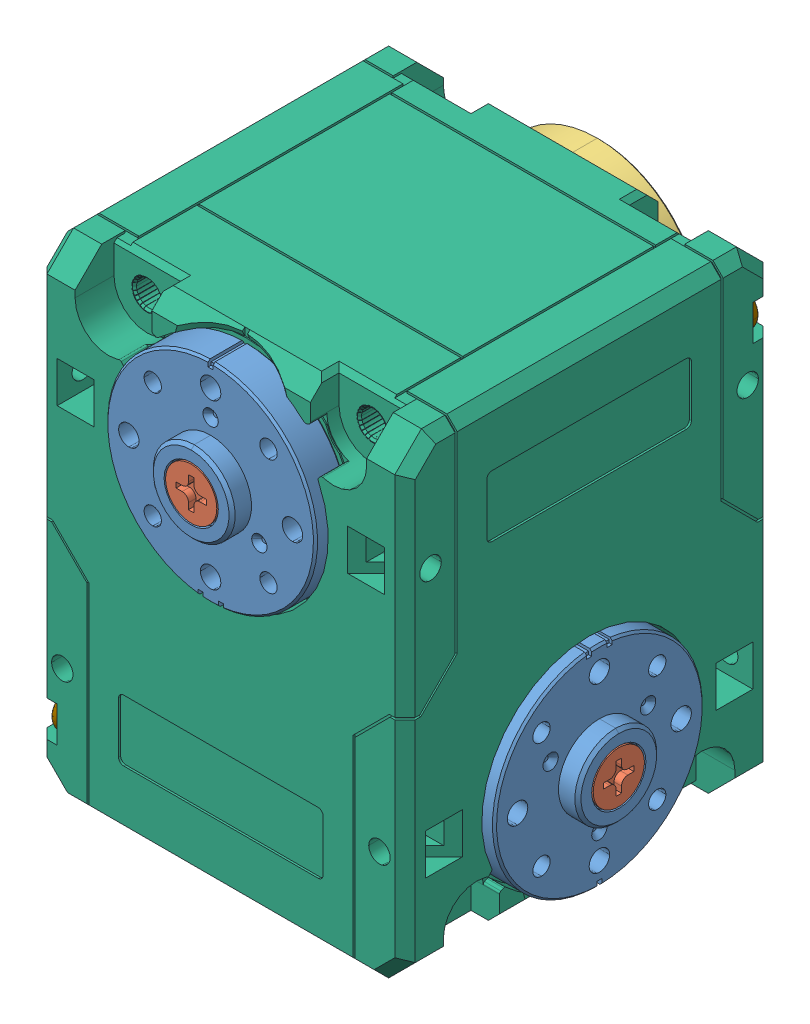
SolidWorks assembly 2XL-430, configuration Default. Lengths in mm.
Overall size (40.9 46.5 40.9).
34 component instances, 11 part files, 0 mates.
Components (placement in the parent):
- 2XL-430.stp-1: 2XL-430.stp [Default] at origin size (40.9 46.5 40.9)
  - DC11_A01_HORN_REF_ASM.stp-1: DC11_A01_HORN_REF_ASM.stp [Default] at (15.5 -12 0) x (0 -1 0) z (0 0 1) size (20.5 6.01 20.5)
    - DC11_A01_HORN_REF.stp-1: DC11_A01_HORN_REF.stp [Default] at origin size (20.5 5.4 20.5)
    - FHS_M2_5X06_NYLOK.stp-1: FHS_M2_5X06_NYLOK.stp [Default] at (0 3.95 0) size (5 6.01 5)
  - DC11_A01_HORN_REF_ASM.stp-2: DC11_A01_HORN_REF_ASM.stp [Default] at (0 12 15.5) x (0 1 0) z (1 0 0) size (20.5 6.01 20.5)
    - DC11_A01_HORN_REF.stp-1: DC11_A01_HORN_REF.stp [Default] at origin size (20.5 5.4 20.5)
    - FHS_M2_5X06_NYLOK.stp-1: FHS_M2_5X06_NYLOK.stp [Default] at (0 3.95 0) size (5 6.01 5)
  - DC11_A01_IDLER_REF_ASM.stp-1: DC11_A01_IDLER_REF_ASM.stp [Default] at (-19 -12 0) x (0 1 0) z (0 0 1) size (20.5 8.41 20.5)
    - DC11_A01_IDLER_REF.stp-1: DC11_A01_IDLER_REF.stp [Default] at origin size (20.5 3.5 20.5)
    - DC11_A01_IDLER_CAP_REF.stp-1: DC11_A01_IDLER_CAP_REF.stp [Default] at (0 -0.2 0) x (1 0 0) z (0 0 -1) size (10.1 5.2 10.37)
    - DC11_A01_IDLER_SCREW.stp-1: DC11_A01_IDLER_SCREW.stp [Default] at (0 -3.9 0) size (5 5.01 5)
  - DC11_A01_IDLER_REF_ASM.stp-2: DC11_A01_IDLER_REF_ASM.stp [Default] at (0 12 -19) x (0 -1 0) z (1 0 0) size (20.5 8.41 20.5)
    - DC11_A01_IDLER_REF.stp-1: DC11_A01_IDLER_REF.stp [Default] at origin size (20.5 3.5 20.5)
    - DC11_A01_IDLER_CAP_REF.stp-1: DC11_A01_IDLER_CAP_REF.stp [Default] at (0 -0.2 0) x (1 0 0) z (0 0 -1) size (10.1 5.2 10.37)
    - DC11_A01_IDLER_SCREW.stp-1: DC11_A01_IDLER_SCREW.stp [Default] at (0 -3.9 0) size (5 5.01 5)
  - DC14_A01_REF.stp-1: DC14_A01_REF.stp [Default] at origin size (37 46.5 37)
  - S3B-EH.stp-1: S3B-EH.stp [Default] at (-8.5 1.2 -5.9) x (0 0 -1) z (0 1 0) size (10 7.4 8.2)
  - S3B-EH.stp-2: S3B-EH.stp [Default] at (-5.9 -1.2 -8.5) x (-1 0 0) z (0 -1 0) size (10 7.4 8.2)
  - EHR-3.stp-1: EHR-3.stp [Default] at (-18.05 3.85 -3.5) x (0 0 -1) z (0 -1 0) size (9.5 3.8 7.1)
  - EHR-3.stp-2: EHR-3.stp [Default] at (-3.5 -3.85 -18.05) x (-1 0 0) z (0 1 0) size (9.5 3.8 7.1)
  - PHS_M2X33_TAP_K.stp-1: PHS_M2X33_TAP_K.stp [Default] at (-16 -17 -16) x (0 1 0) z (0 0 1) size (3.5 34.47 3.5)
  - PHS_M2X33_TAP_K.stp-2: PHS_M2X33_TAP_K.stp [Default] at (-16 -17 16) x (0 1 0) z (0 0 1) size (3.5 34.47 3.5)
  - PHS_M2X33_TAP_K.stp-3: PHS_M2X33_TAP_K.stp [Default] at (-16 17 -16) x (1 0 0) z (0 1 0) size (3.5 34.47 3.5)
  - PHS_M2X33_TAP_K.stp-4: PHS_M2X33_TAP_K.stp [Default] at (16 17 -16) x (1 0 0) z (0 1 0) size (3.5 34.47 3.5)
  - DC14_A01_INSERT_2.stp-1: DC14_A01_INSERT_2.stp [Default] at (-10.9 -20 11) x (0 1 0) z (0 0 1) size (3.48 3.31 3.48)
  - DC14_A01_INSERT_2.stp-2: DC14_A01_INSERT_2.stp [Default] at (-10.9 -20 -11) x (0 1 0) z (0 0 1) size (3.48 3.31 3.48)
  - DC14_A01_INSERT_2.stp-3: DC14_A01_INSERT_2.stp [Default] at (10.9 -20 -11) x (0 -1 0) z (0 0 1) size (3.48 3.31 3.48)
  - DC14_A01_INSERT_2.stp-4: DC14_A01_INSERT_2.stp [Default] at (10.9 -20 11) x (0 -1 0) z (0 0 1) size (3.48 3.31 3.48)
  - DC14_A01_INSERT_2.stp-5: DC14_A01_INSERT_2.stp [Default] at (-11 20 -10.9) x (1 0 0) z (0 1 0) size (3.48 3.31 3.48)
  - DC14_A01_INSERT_2.stp-6: DC14_A01_INSERT_2.stp [Default] at (11 20 -10.9) x (1 0 0) z (0 1 0) size (3.48 3.31 3.48)
  - DC14_A01_INSERT_2.stp-7: DC14_A01_INSERT_2.stp [Default] at (11 20 10.9) x (-1 0 0) z (0 1 0) size (3.48 3.31 3.48)
  - DC14_A01_INSERT_2.stp-8: DC14_A01_INSERT_2.stp [Default] at (-11 20 10.9) x (-1 0 0) z (0 1 0) size (3.48 3.31 3.48)
  - DC14_A01_INSERT_1.stp-1: DC14_A01_INSERT_1.stp [Default] at (0 12 -14.8) x (-1 0 0) z (0 1 0) size (3.98 3.31 3.98)
  - DC14_A01_INSERT_1.stp-2: DC14_A01_INSERT_1.stp [Default] at (-14.8 -12 0) x (0 -1 0) z (0 0 1) size (3.98 3.31 3.98)
